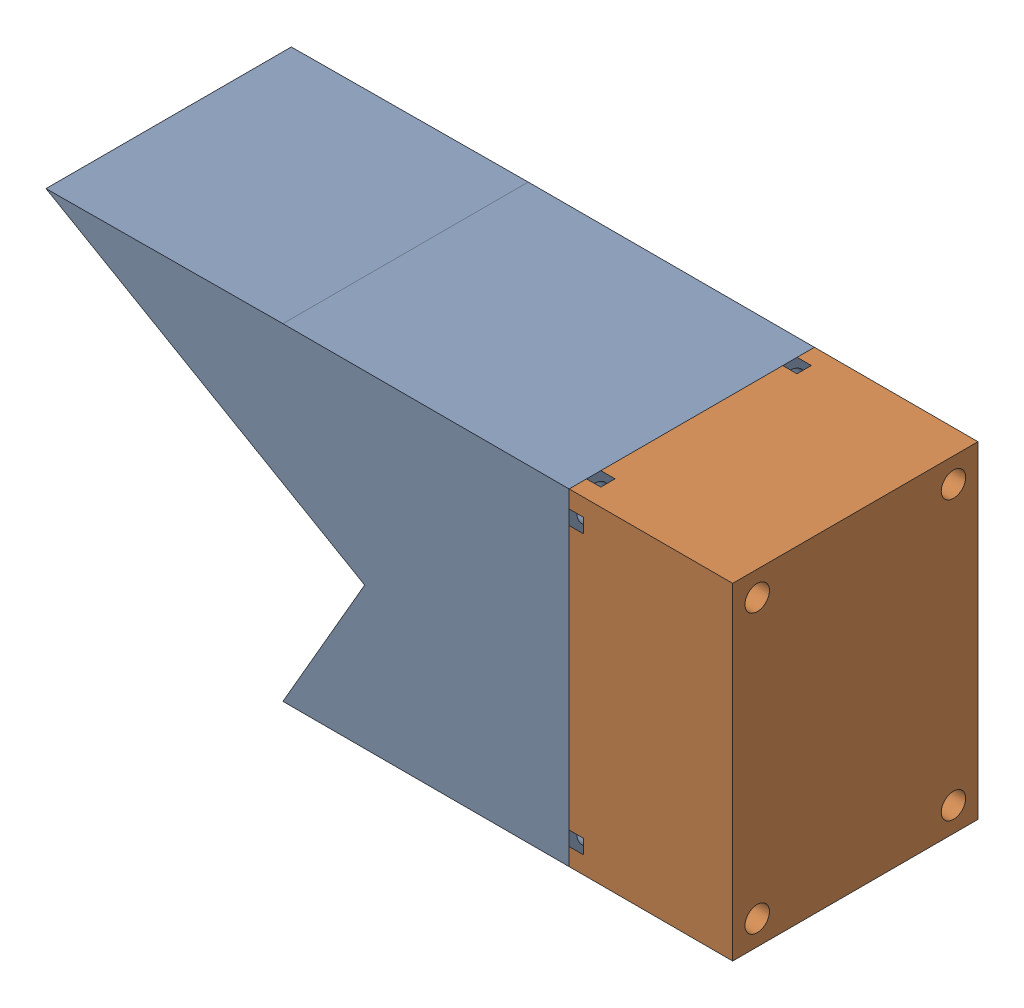
SolidWorks assembly MirrorNacelle Assembly, configuration Default. Lengths in mm.
Overall size (106.64 50.8 38.1).
2 component instances, 2 part files, 0 mates.
Components (placement in the parent):
- MirrorCalf Nacelle-1: MirrorCalf Nacelle [Default] at (1.6936 15.1916 -38.1993) size (81.24 50.8 38.1)
- MotorEndcap-1: MotorEndcap [Default] at (31.0235 2.2988 -24.7342) x (0 0 1) z (-1 0 0) size (38.1 50.8 25.4)
